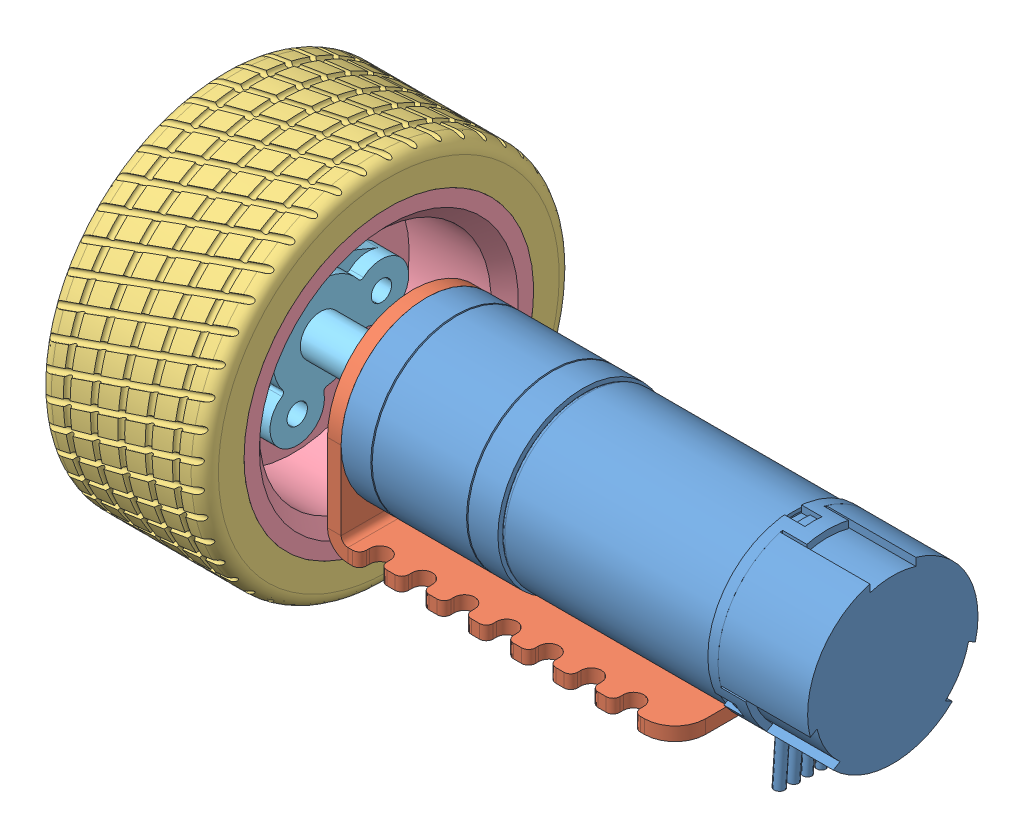
SolidWorks assembly 01.01.01_Motor_Mount, configuration Default. Lengths in mm.
Overall size (98.45 70.56 70.55).
6 component instances, 5 part files, 9 mates.
Components (placement in the parent):
- 25d-metal-gearmotor-75-99-encoder.step-1: 25d-metal-gearmotor-75-99-encoder.step [Default] at (2 14.5 -12.5) x (0 0 -1) z (-1 0 0) size (25 30.75 80.95)
- Pololu 25D mm Metal Gearmotor Bracket-1: Pololu 25D mm Metal Gearmotor Bracket [Default] at origin size (51 27 25)
- 56mm tires v1.step-1: 56mm tires v1.step [Default] at (-15.75 14.5 -12.5) x (0 0.382108 0.924118) z (0 -0.924118 0.382108) size (54 27.5 54.02)
  - ties.step-1: ties.step [Default] at origin size (54 24.5 54.02)
  - wheel.step-1: wheel.step [Default] at origin size (42.5 24.5 42.5)
  - connector.step-1: connector.step [Default] at origin size (23.59 17 21.5)
Mates (geometry in assembly coordinates):
- Coincident1: coincident aligned: plane of Pololu 25D mm Metal Gearmotor Bracket-1 through (0 0 0) normal (1 0 0)
- Coincident2: coincident aligned: plane of Pololu 25D mm Metal Gearmotor Bracket-1 through (0 0 0) normal (0 1 0)
- Coincident3: coincident aligned: plane of Pololu 25D mm Metal Gearmotor Bracket-1 through (0 0 0) normal (1 0 0)
- Coincident4: coincident aligned: plane of Pololu 25D mm Metal Gearmotor Bracket-1 through (0 0 0) normal (0 0 1)
- Coincident5: coincident anti-aligned: plane of 25d-metal-gearmotor-75-99-encoder.step-1 through (2 -2.5 -12.5248) normal (-1 0 0); plane of Pololu 25D mm Metal Gearmotor Bracket-1 through (2 0 0) normal (1 0 0)
- Concentric3: concentric anti-aligned: cylinder of 25d-metal-gearmotor-75-99-encoder.step-1 through (2 -2.5 -12.5248) axis (-1 0 0) radius 2; cylinder of 56mm tires v1.step-1/connector.step-1 through (-15.5 -2.5 -12.5248) axis (1 0 0) radius 1.5
- Coincident6: coincident anti-aligned: plane of 25d-metal-gearmotor-75-99-encoder.step-1 through (-0.5 -2.5 -12.5248) normal (-1 0 0); plane of 56mm tires v1.step-1/connector.step-1 through (-0.5 -2.5 -12.5248) normal (1 0 0)
- Concentric4: concentric anti-aligned: cylinder of 25d-metal-gearmotor-75-99-encoder.step-1 through (4.85 6 -12.5) axis (-1 0 0) radius 1.25; cylinder of Pololu 25D mm Metal Gearmotor Bracket-1 through (2 6 -12.5) axis (1 0 0) radius 1.65
- Concentric5: concentric anti-aligned: cylinder of 25d-metal-gearmotor-75-99-encoder.step-1 through (4.85 -10.9999 -12.5497) axis (-1 0 0) radius 1.25; cylinder of Pololu 25D mm Metal Gearmotor Bracket-1 through (2 23 -12.5) axis (1 0 0) radius 1.65
